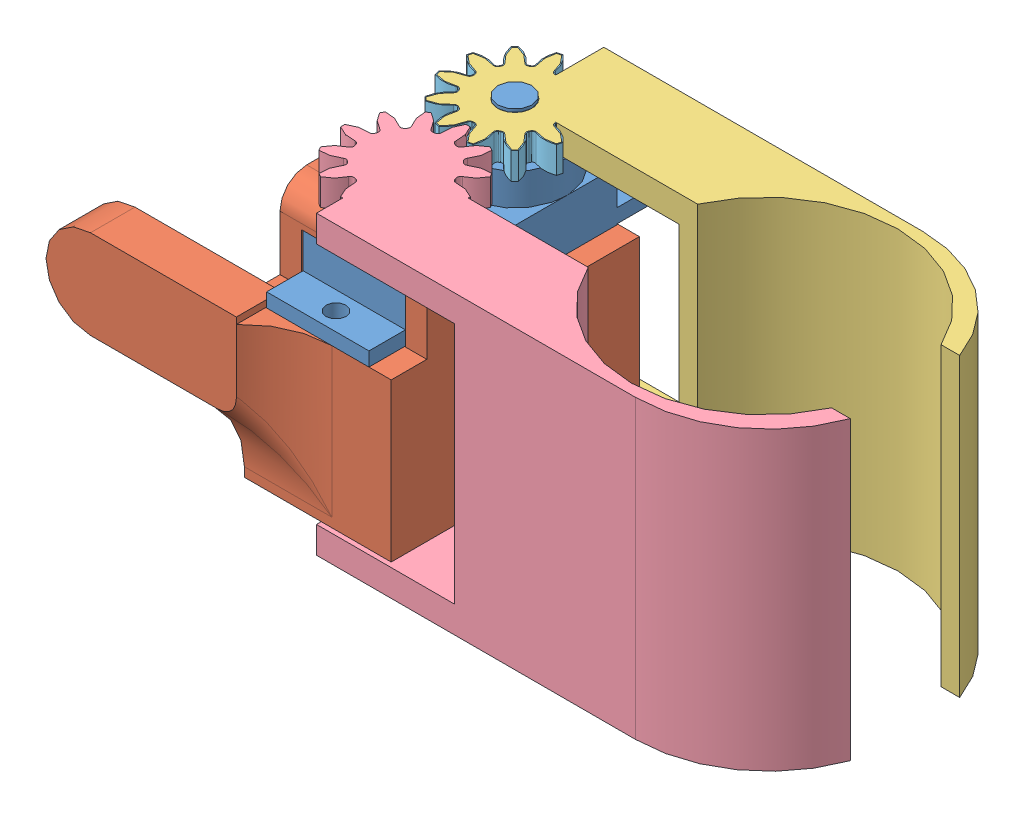
SolidWorks assembly Gripper, configuration Default. Lengths in mm.
Overall size (77.25 33.63 35.45).
6 component instances, 5 part files, 13 mates.
Components (placement in the parent):
- SG90MicroServo-1: SG90MicroServo [Default] x (0 0 -1) z (0 1 0) size (32 11.5 27.24)
- GripperBody-1: GripperBody [Default] at origin size (35.5 26.91 31.2)
- FingerDriver-1: FingerDriver [Default] at (0 10.2641 -6.15) size (56.87 33.3 16.87)
- FingerFollower-1: FingerFollower [Default] at (0 10.2641 6.15) x (1 0 0) z (0 0 -1) size (57.05 33.3 17.05)
- GripperGear-1: GripperGear [Default] at (0 25.4141 -6.15) x (1 0 0) z (0 -1 0) size (13.95 13.95 3) (hidden)
- GripperGear-2: GripperGear [Default] at (0 25.4141 6.15) x (0.965926 0 0.258819) z (0 -1 0) size (13.95 13.95 3) (hidden)
Mates (geometry in assembly coordinates):
- Concentric1: concentric aligned: cylinder of SG90MicroServo-1 through (0 32.6579 -6.15) axis (0 -1 0) radius 1.915; cylinder of FingerDriver-1 through (0 -0.3859 -6.15) axis (0 -1 0) radius 1.95
- Coincident1: coincident anti-aligned: plane of FingerDriver-1 through (0 23.9141 -6.15) normal (0 -1 0); plane of SG90MicroServo-1 through (0 23.9141 0) normal (0 1 0)
- Concentric2: concentric aligned: cylinder of GripperBody-1 through (0 20.9141 6.15) axis (0 1 0) radius 2.075; cylinder of FingerFollower-1 through (0 20.9141 6.15) axis (0 1 0) radius 1.95
- Coincident2: coincident anti-aligned: plane of GripperBody-1 through (0 23.9141 0) normal (0 1 0); plane of FingerFollower-1 through (0 23.9141 6.15) normal (0 -1 0)
- GearMate1: gear = 1 : 1 mm: cylinder of FingerDriver-1 through (0 4.4874 -6.15) axis (0 1 0) radius 4.5986; cylinder of FingerFollower-1 through (0 3.9737 6.15) axis (0 1 0) radius 4.5986
- Concentric3: concentric anti-aligned: cylinder of FingerDriver-1 through (0 4.4874 -6.15) axis (0 1 0) radius 4.5986; cylinder of GripperGear-1 through (0 26.9141 -6.15) axis (0 -1 0) radius 4.6986
- Coincident3: coincident aligned: plane of FingerDriver-1 through (0 26.9141 -6.15) normal (0 1 0); plane of GripperGear-1 through (0 26.9141 -6.15) normal (0 1 0)
- Parallel1: parallel aligned: plane of FingerDriver-1 through (0 10.2641 -6.15) normal (1 0 0); plane of GripperGear-1 through (0 25.4141 -6.15) normal (1 0 0)
- Concentric4: concentric anti-aligned: cylinder of FingerFollower-1 through (0 3.9737 6.15) axis (0 1 0) radius 4.5986; cylinder of GripperGear-2 through (0 26.9141 6.15) axis (0 -1 0) radius 4.6986
- Coincident5: coincident aligned: plane of FingerFollower-1 through (0 26.9141 6.15) normal (0 1 0); plane of GripperGear-2 through (0 26.9141 6.15) normal (0 1 0)
- Angle2: planar angle = 0.261799 rad aligned: plane of FingerFollower-1 through (0 10.2641 6.15) normal (1 0 0); plane of GripperGear-2 through (0 25.4141 6.15) normal (0.965926 0 0.258819)
- Parallel2: parallel aligned: plane of GripperBody-1 through (8.25 -3 -11.9) normal (0 0 -1); plane of FingerDriver-1 through (0 26.9141 -16.15) normal (0 0 -1)
- Parallel3: parallel aligned: plane of GripperBody-1 through (8.25 -3 16) normal (0 0 1); plane of FingerFollower-1
